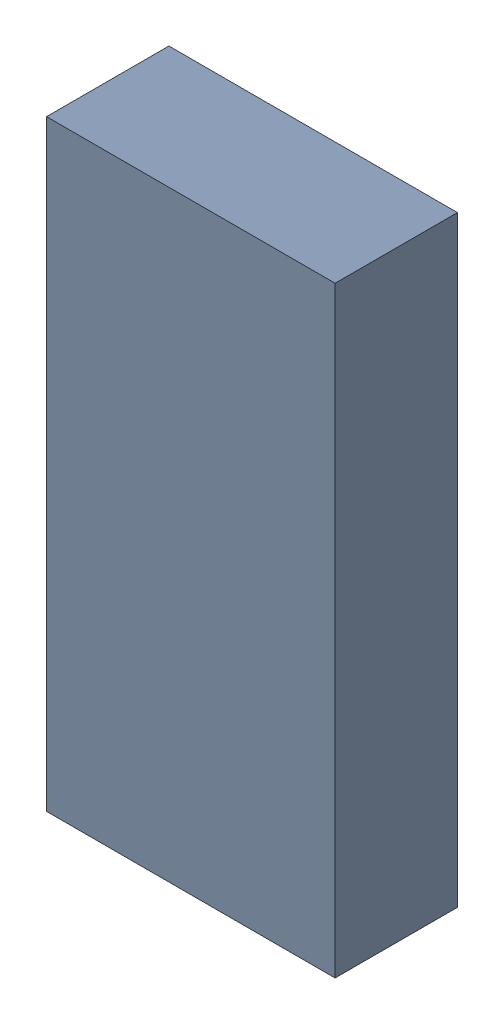
SolidWorks assembly 6327396928, configuration Default. Lengths in mm.
Overall size (0.6 1.25 0.25).
2 component instances, 1 part files, 0 mates.
Components (placement in the parent):
- 6701982208-1:  [Default] at (27.7 14.8 0) (suppressed, hidden)
- Extruded-3-1: Extruded-3 [Default] at origin size (0.6 1.25 0.25)
